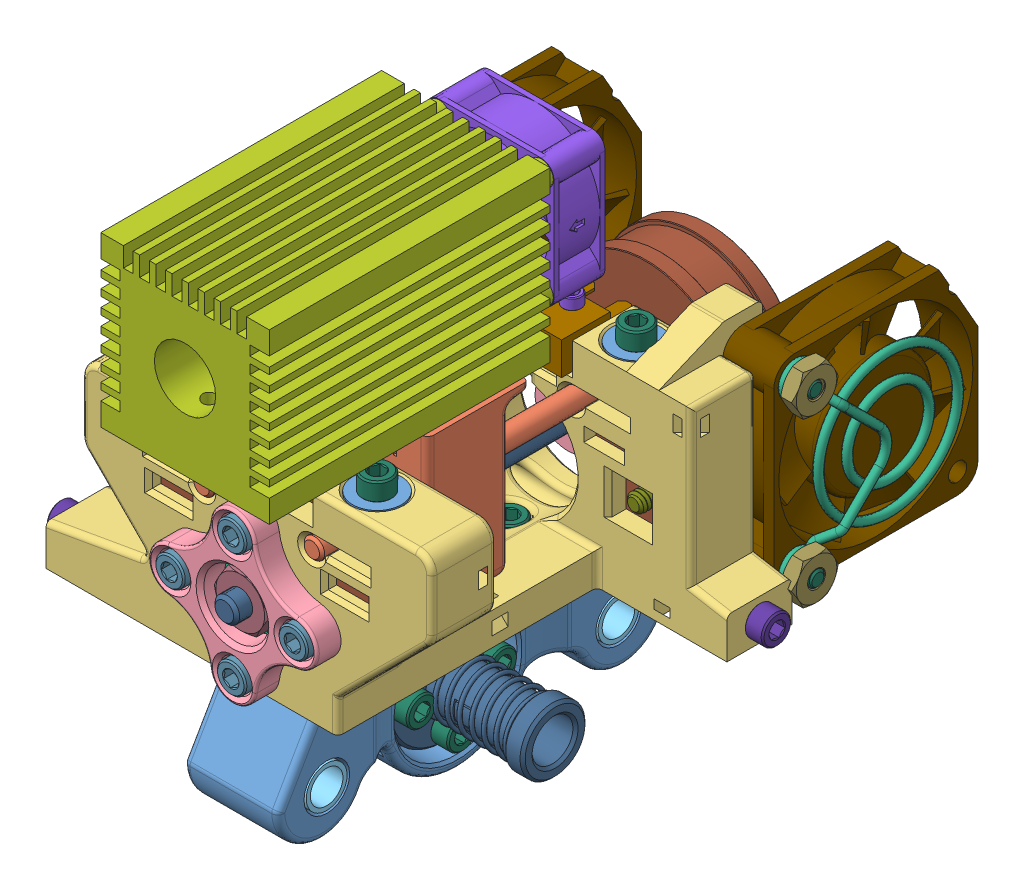
SolidWorks assembly LCSA-3, configuration LCSA-3. Lengths in mm.
Overall size (89.88 103.22 117.36).
86 component instances, 29 part files, 228 mates.
Components (placement in the parent):
- LCSAP-304-1: LCSAP-304 [LCSAP-304] at (-4.5942 14.1847 0) size (19.04 26.86 76.19)
- LCSAP-301-1: LCSAP-301 [LCSAP-301] at (12.8683 56.7614 1.1334) x (-1 0 0) z (0 1 0) size (35.07 23.37 31.49)
- LCSAP-302-1: LCSAP-302 [LCSAP-302] at (-20.4692 28.2182 33.02) x (0 0 -1) z (1 0 0) size (76.2 44.7 82.55)
- LCSAP-303-1: LCSAP-303 [LCSAP-303] at (-4.5942 44.7282 33.02) x (0 -1 0) z (0 0 1) size (33.02 33.02 4.76)
- 6659K650-1: 6659K650 [6659K65] at (6.2008 57.4282 1.1334) x (1 0 0) z (0 -1 0) size (10 6 10)
- 6659K650-2: 6659K650 [6659K65] at (-15.3892 57.4282 1.1334) x (-0.173648 -0.984808 0) z (-0.984808 0.173648 0) size (10 6 10)
- 19155K910-1: 19155K910 [19155K91] at (-42.5342 50.5682 -50.29) x (0 0 -1) z (0 1 0) size (34.05 4.8 39.2)
- 19155K910-2: 19155K910 [19155K91] at (33.3458 50.5682 -50.29) x (0 0 -1) z (0 -1 0) size (34.05 4.8 39.2)
- 94855A279-1: 94855A279 [94855A279] at (-9.3617 59.8094 -23.9712) size (4.76 1.94 4.76)
- 94855A279-2: 94855A279 [94855A279] at (0.1683 59.8094 -23.9712) x (0 0 -1) z (1 0 0) size (4.76 1.94 4.76)
- 94855A279-7: 94855A279 [94855A279] at (0.1683 59.8094 26.5113) x (0 0 -1) z (-1 0 0) size (4.76 1.94 4.76)
- 94855A279-8: 94855A279 [94855A279] at (-9.3567 59.8094 26.5113) x (0 0 -1) z (-1 0 0) size (4.76 1.94 4.76)
- 92185A081-1: 92185A081 [92185A081] at (0.1683 56.5257 -23.9712) x (0 0 1) z (0 -1 0) size (3.56 3.56 13.6)
- 92185A081-2: 92185A081 [92185A081] at (-9.3617 56.5257 -23.9712) x (0 0 1) z (0 -1 0) size (3.56 3.56 13.6)
- 92185A081-7: 92185A081 [92185A081] at (-9.3617 56.5257 26.5113) x (0 0 -1) z (0 -1 0) size (3.56 3.56 13.6)
- 92185A081-8: 92185A081 [92185A081] at (0.1683 56.5257 26.5113) x (0 0 -1) z (0 -1 0) size (3.56 3.56 13.6)
- 94855A283-6: 94855A283 [94855A283] at (-4.5942 44.7282 12.8809) x (0 -1 0) z (1 0 0) size (9.53 3.79 9.53)
- 90322A641-1: 90322A641 [90322A641] at (-4.5942 44.7282 4.445) x (0 0 -1) z (-0.968717 -0.248166 0) size (69.85 4.83 4.83)
- 94855A201-1: 94855A201 [94855A201] at (-4.5942 17.4311 16.51) x (0 0 -1) z (-1 0 0) size (7.94 3.39 7.94)
- 94855A201-2: 94855A201 [94855A201] at (-4.5942 17.4311 -16.51) x (0 0 1) z (1 0 0) size (7.94 3.39 7.94)
- 94855A201-3: 94855A201 [94855A201] at (7.4708 44.7282 30.48) x (-0.104528 -0.994522 0) z (-0.994522 0.104528 0) size (7.94 3.39 7.94)
- 94855A201-4: 94855A201 [94855A201] at (-21.8027 52.8641 26.67) x (0 0 1) z (1 0 0) size (7.94 3.39 7.94)
- 94855A201-5: 94855A201 [94855A201] at (12.6143 52.8641 26.67) x (0 0 -1) z (1 0 0) size (7.94 3.39 7.94)
- 94855A201-6: 94855A201 [94855A201] at (-4.5942 32.6632 30.48) x (0 1 0) z (-1 0 0) size (7.94 3.39 7.94)
- 94855A201-7: 94855A201 [94855A201] at (-16.6592 44.7282 30.48) x (0.994522 0.104528 0) z (-0.104528 0.994522 0) size (7.94 3.39 7.94)
- 94855A201-8: 94855A201 [94855A201] at (-21.8027 52.8641 -24.13) x (0 0 1) z (-1 0 0) size (7.94 3.39 7.94)
- 94855A283-5: 94855A283 [94855A283] at (-4.5942 44.7282 5.2609) x (0 -1 0) z (1 0 0) size (9.53 3.79 9.53)
- 94855A201-9: 94855A201 [94855A201] at (12.6143 52.8641 -24.13) x (0 0 -1) z (-1 0 0) size (7.94 3.39 7.94)
- 94855A201-11: 94855A201 [94855A201] at (-4.5942 56.7932 30.48) x (1 0 0) z (0 -1 0) size (7.94 3.39 7.94)
- 94855A201-13: 94855A201 [94855A201] at (16.2417 32.1869 -24.13) x (0 1 0) z (0 0 -1) size (7.94 3.39 7.94)
- 94855A201-15: 94855A201 [94855A201] at (-25.4301 32.1869 26.67) x (0 1 0) z (0 0 1) size (7.94 3.39 7.94)
- 94855A201-16: 94855A201 [94855A201] at (17.3558 44.7282 -22.7409) x (0 -1 0) z (1 0 0) size (7.94 3.39 7.94)
- 94855A201-18: 94855A201 [94855A201] at (-26.5442 44.7282 -22.7409) x (0 1 0) z (-1 0 0) size (7.94 3.39 7.94)
- 90480A007-1: 90480A007 [90480A007] at (-12.3333 15.6452 7.9375) x (0 -0.866025 -0.5) z (0 0.5 -0.866025) size (7.94 3.39 9.17)
- 90480A007-2: 90480A007 [90480A007] at (-12.3333 15.6452 -7.9375) x (0 -0.866025 0.5) z (0 -0.5 -0.866025) size (7.94 3.39 9.17)
- 90480A195-1: 90480A195 [90480A195] at (-4.5942 44.7282 34.6575) x (0 1 0) z (1 0 0) size (9.53 3.99 11)
- 90480A195-4: 90480A195 [90480A195] at (-4.5942 44.7282 26.4825) x (-0.866025 0.5 0) z (-0.5 -0.866025 0) size (9.53 3.99 11)
- 90480A007-3: 90480A007 [90480A007] at (-12.3333 7.7077 0) x (0 -0.5 0.866025) z (0 -0.866025 -0.5) size (7.94 3.39 9.17)
- 90480A007-5: 90480A007 [90480A007] at (-12.3333 23.5827 0) x (0 -0.5 0.866025) z (0 -0.866025 -0.5) size (7.94 3.39 9.17)
- 90480A007-7: 90480A007 [90480A007] at (-45.5233 34.5682 -34.29) x (0 0.5 -0.866025) z (0 0.866025 0.5) size (7.94 3.39 9.17)
- 90480A007-9: 90480A007 [90480A007] at (-45.5233 66.5682 -34.29) x (0 0.5 -0.866025) z (0 0.866025 0.5) size (7.94 3.39 9.17)
- 90480A007-11: 90480A007 [90480A007] at (36.3349 34.5682 -34.29) x (0 -0.5 -0.866025) z (0 -0.866025 0.5) size (7.94 3.39 9.17)
- 90480A007-13: 90480A007 [90480A007] at (36.3349 66.5682 -34.29) x (0 -0.5 -0.866025) z (0 -0.866025 0.5) size (7.94 3.39 9.17)
- 92196A145-5: 92196A145 [92196A145] at (-4.5942 56.7932 26.67) x (-0.805768 -0.592231 0) z (0 0 -1) size (5.74 5.74 11.87)
- 92196A145-6: 92196A145 [92196A145] at (7.4708 44.7282 26.67) x (-0.5 0.866025 0) z (0 0 -1) size (5.74 5.74 11.87)
- 92196A145-7: 92196A145 [92196A145] at (-16.6592 44.7282 26.67) x (-0.20766 0.978201 0) z (0 0 -1) size (5.74 5.74 11.87)
- 92196A145-8: 92196A145 [92196A145] at (-4.5942 32.6632 26.67) x (0.437601 -0.899169 0) z (0 0 -1) size (5.74 5.74 11.87)
- 92196A150-6: 92196A150 [92196A150] at (12.6143 51.5862 -24.13) x (0.866025 0 0.5) z (0 -1 0) size (5.74 5.74 19.85)
- 92196A150-7: 92196A150 [92196A150] at (12.6143 51.5862 26.67) x (0.866025 0 0.5) z (0 -1 0) size (5.74 5.74 19.85)
- 92196A150-9: 92196A150 [92196A150] at (-21.8027 51.5862 26.67) x (0.866025 0 0.5) z (0 -1 0) size (5.74 5.74 19.85)
- 92196A150-11: 92196A150 [92196A150] at (-21.8027 51.5862 -24.13) x (0.866025 0 0.5) z (0 -1 0) size (5.74 5.74 19.85)
- 92196A150-1: 92196A150 [92196A150] at (-16.6592 15.6452 7.9375) x (0 0.445229 0.895417) z (-1 0 0) size (5.74 5.74 19.85)
- 92196A150-2: 92196A150 [92196A150] at (-16.6592 15.6452 -7.9375) x (0 0.5 0.866025) z (-1 0 0) size (5.74 5.74 19.85)
- 92196A150-3: 92196A150 [92196A150] at (-4.5942 13.9307 16.51) x (0.884768 0 0.466031) z (0 -1 0) size (5.74 5.74 19.85)
- 92196A150-4: 92196A150 [92196A150] at (-4.5942 13.9307 -16.51) x (0.997638 0 -0.068685) z (0 -1 0) size (5.74 5.74 19.85)
- 92196A150-13: 92196A150 [92196A150] at (-16.6592 7.7077 0) x (0 -0.959127 0.282977) z (-1 0 0) size (5.74 5.74 19.85)
- 92196A150-15: 92196A150 [92196A150] at (-16.6592 23.5827 0) x (0 0.993694 -0.112128) z (-1 0 0) size (5.74 5.74 19.85)
- 92196A150-17: 92196A150 [92196A150] at (37.9933 34.5682 -34.29) x (0 0.866025 -0.5) z (1 0 0) size (5.74 5.74 19.85)
- 92196A150-19: 92196A150 [92196A150] at (37.6333 66.5682 -34.29) x (0 0.755509 0.655138) z (1 0 0) size (5.74 5.74 19.85)
- 92196A150-21: 92196A150 [92196A150] at (-47.1817 34.5682 -34.29) x (0 0.866025 0.5) z (-1 0 0) size (5.74 5.74 19.85)
- 92196A150-23: 92196A150 [92196A150] at (-46.8217 66.5682 -34.29) x (0 -0.795652 -0.605754) z (-1 0 0) size (5.74 5.74 19.85)
- 92196A153-1: 92196A153 [92196A153] at (-26.5442 44.7282 -18.78) size (5.74 5.74 29.4)
- 92196A153-2: 92196A153 [92196A153] at (17.3558 44.7282 -18.78) x (0.987351 0.158553 0) z (0 0 1) size (5.74 5.74 29.4)
- 92196A236-1: 92196A236 [92196A236] at (1.7558 32.1869 -24.13) x (0 0.971198 -0.238273) z (-1 0 0) size (5.74 5.74 38.92)
- 92196A236-2: 92196A236 [92196A236] at (-10.9442 32.1869 26.67) x (0 0.996692 0.081273) z (1 0 0) size (5.74 5.74 38.92)
- AD0412HB-G70-1: AD0412HB-G70 [AD0412HB-G70] at (23.3458 50.5682 -50.29) x (0 -1 0) z (1 0 0) size (40 40 10.64)
- AD0412HB-G70-2: AD0412HB-G70 [AD0412HB-G70] at (-42.5342 50.5682 -50.29) x (0 -1 0) z (1 0 0) size (40 40 10.64)
- 90126A509-1: 90126A509 [90126A509] at (12.6143 66.3182 -24.13) x (-0.715617 0 -0.698492) z (0.698492 0 -0.715617) size (9.53 1.14 9.53)
- 90126A509-2: 90126A509 [90126A509] at (12.6143 66.3182 26.67) x (-0.834429 0 -0.551115) z (0.551115 0 -0.834429) size (9.53 1.14 9.53)
- 90126A509-4: 90126A509 [90126A509] at (-21.8027 66.3182 26.67) x (-0.933615 0 -0.358277) z (0.358277 0 -0.933615) size (9.53 1.14 9.53)
- 90126A509-6: 90126A509 [90126A509] at (-21.8027 66.3182 -24.13) x (-0.991589 0 -0.129423) z (0.129423 0 -0.991589) size (9.53 1.14 9.53)
- 6112K34-2.5-1: 6112K34-2.5 [6112K34] at (6.2008 57.4282 -30.48) x (-1 0 0) z (0 0 1) size (4 4 63.5)
- 6112K34-2.5-2: 6112K34-2.5 [6112K34] at (-15.3892 57.4282 33.02) x (1 0 0) z (0 0 -1) size (4 4 63.5)
- 91292A113-1: 91292A113 [91292A113] at (3.6558 80.8289 -2.9306) x (-0.866025 0 0.5) z (0 1 0) size (5.5 5.5 13.21)
- 91292A113-2: 91292A113 [91292A113] at (-4.5942 80.8008 -2.9306) x (-0.866025 0 0.5) z (0 1 0) size (5.5 5.5 13.21)
- 91292A113-3: 91292A113 [91292A113] at (-12.8442 80.8289 -2.9306) x (-0.866025 0 0.5) z (0 1 0) size (5.5 5.5 13.21)
- WXZC000198-2-1: WXZC000198-2 [WXZC000198-2 ] at (-4.5942 44.7282 -27.845) x (-0.598924 0.800806 0) z (0 0 -1) size (12.67 12.7 12.7)
- 1688K300-1: 1688K300 [1688K3] at (-1.7005 14.1847 28.575) x (0 0 -1) z (-1 0 0) size (7.99 7.99 12.7)
- 1688K300-2: 1688K300 [1688K3] at (-1.7005 14.1847 -28.575) x (0 0.158553 -0.987351) z (-1 0 0) size (7.99 7.99 12.7)
- R1810-2Z-1: R1810-2Z [6153K15] at (-4.5942 44.7282 28.07) x (0.999864 -0.016468 0) z (0 0 1) size (16 16 5)
- 5.6MMTO18AC-1: 5.6MMTO18AC [5.6MMTO18AC] at (11.9058 104.5823 47.0694) x (-1 0 0) z (0 0 1) size (33 33 59.76)
- 2510S-1: 2510S [2510S] at (-4.5942 88.0823 -12.6931) x (0 1 0) z (0 0 -1) size (25 25 10)
- 19N602-1: 19N602 [19N602] at (5.2983 61.2382 -26.3212) x (-1 0 0) z (0 0 -1) size (19.9 6.4 16.76)
- 19N602-4: 19N602 [19N602] at (5.2983 67.6382 28.8613) x (-1 0 0) z (0 0 1) size (19.9 6.4 16.76)
- T8-AB-1: T8-AB [T8-AB] at (-4.5942 15.6452 0) x (0 -1 0) z (0 0 1) size (22.23 25.4 22.23)
- 14HR05-0504S-1: 14HR05-0504S [14HR05-0504S] at (-4.5942 44.7282 -43.18) size (50.25 36.5 24.5)
Mates (geometry in assembly coordinates):
- Coincident31: coincident anti-aligned: plane of LCSAP-304-1 through (-4.5942 18.8202 0) normal (0 -1 0); plane of 94855A201-1 through (-8.5629 18.8202 20.4788) normal (0 1 0)
- Concentric13: concentric anti-aligned: circle of LCSAP-304-1; circle of 94855A201-1
- Coincident32: coincident anti-aligned: plane of LCSAP-304-1 through (-8.5629 18.8202 20.4788) normal (1 0 0); plane of 94855A201-1 through (-8.5629 16.0421 20.4788) normal (-1 0 0)
- Coincident33: coincident anti-aligned: plane of LCSAP-304-1 through (-4.5942 18.8202 0) normal (0 -1 0); plane of 94855A201-2 through (-0.6254 18.8202 -20.4788) normal (0 1 0)
- Concentric14: concentric aligned: circle of LCSAP-304-1; circle of 94855A201-2
- Coincident34: coincident anti-aligned: plane of LCSAP-304-1 through (-0.6254 18.8202 -12.5412) normal (-1 0 0); plane of 94855A201-2 through (-0.6254 16.0421 -20.4788) normal (1 0 0)
- Coincident71: coincident aligned: plane of 92196A145-5 through (-4.5942 56.7932 38.1127) normal (0 0 1); plane of 92196A145-6 through (7.4708 44.7282 38.1127) normal (0 0 1)
- Coincident72: coincident aligned: plane of 92196A145-6 through (7.4708 44.7282 38.1127) normal (0 0 1); plane of 92196A145-8 through (-4.5942 32.6632 38.1127) normal (0 0 1)
- Coincident73: coincident aligned: plane of 92196A145-7 through (-16.6592 44.7282 38.1127) normal (0 0 1); plane of 92196A145-8 through (-4.5942 32.6632 38.1127) normal (0 0 1)
- Concentric51: concentric aligned: circle of LCSAP-301-1; circle of 94855A283-5
- Coincident78: coincident anti-aligned: plane of LCSAP-301-1 through (0.0413 48.0302 6.8484) normal (0 0 -1); plane of 94855A283-5 through (0.1683 49.4907 6.8484) normal (0 0 1)
- Parallel24: parallel aligned: plane of LCSAP-301-1 through (12.8683 40.0927 1.1334) normal (0 -1 0); plane of 94855A283-5 through (-9.3567 39.9657 3.6734) normal (0 -1 0)
- Concentric53: concentric aligned: circle of WXZC000198-2-1; cylinder of 90322A641-1 through (-4.5942 44.7282 39.37) axis (0 0 -1) radius 2.413
- Coincident84: coincident anti-aligned: cylinder of 90322A641-1 through (-4.5942 44.7282 39.37) axis (0 0 -1) radius 2.413; circle of 90480A195-1
- Coincident86: coincident anti-aligned: plane of R1810-2Z-1 through (-4.5288 48.6964 33.07) normal (0 0 1); plane of 90480A195-1 through (-7.3438 39.9657 33.07) normal (0 0 -1)
- Coincident89: coincident anti-aligned: plane of R1810-2Z-1 through (-4.5288 48.6964 28.07) normal (0 0 -1); plane of 90480A195-4 through (0.9051 44.7282 28.07) normal (0 0 1)
- Coincident90: coincident aligned: cylinder of 90322A641-1 through (-4.5942 44.7282 39.37) axis (0 0 -1) radius 2.413; circle of 90480A195-4
- Concentric54: concentric anti-aligned: circle of 5.6MMTO18AC-1; circle of 2510S-1
- Concentric55: concentric anti-aligned: cylinder of 5.6MMTO18AC-1 through (-14.5942 78.0823 -12.6931) axis (0 0 1) radius 2.3813; circle of 2510S-1
- Coincident91: coincident anti-aligned: plane of 5.6MMTO18AC-1 through (-14.5942 78.0823 -12.6931) normal (0 0 -1); plane of 2510S-1 through (-14.5942 98.0823 -12.6931) normal (0 0 1)
- Concentric56: concentric anti-aligned: plane of LCSAP-301-1; plane of 91292A113-1
- Parallel30: parallel aligned: plane of LCSAP-301-1 through (-22.0567 56.7614 -6.3596) normal (0 0 -1); plane of 91292A113-1 through (4.3775 69.7039 -1.6806) normal (0 0 -1)
- Concentric57: concentric anti-aligned: cylinder of LCSAP-301-1 through (-4.5942 82.8077 -2.9306) axis (0 -1 0) radius 2.8575; cylinder of 91292A113-2 through (-4.5942 67.8008 -2.9306) axis (0 1 0) radius 2.75
- Coincident94: coincident aligned: unknown of 91292A113-2; cone of LCSAP-301-1 through (-4.5942 70.6679 -2.9306) axis (0 1 0)
- Parallel31: parallel aligned: plane of LCSAP-301-1 through (-22.0567 56.7614 -6.3596) normal (0 0 -1); plane of 91292A113-2 through (-3.8725 69.6758 -1.6806) normal (0 0 -1)
- Concentric58: concentric anti-aligned: plane of LCSAP-301-1; plane of 91292A113-3
- Parallel32: parallel aligned: plane of LCSAP-301-1 through (-22.0567 56.7614 -6.3596) normal (0 0 -1); plane of 91292A113-3 through (-12.1225 69.7039 -1.6806) normal (0 0 -1)
- Coincident97: coincident anti-aligned: plane of LCSAP-301-1 through (-22.0567 71.5823 1.1334) normal (0 1 0); plane of 5.6MMTO18AC-1 through (11.9058 71.5823 -7.9306) normal (0 -1 0)
- Concentric64: concentric anti-aligned: circle of 91292A113-1; circle of 5.6MMTO18AC-1
- Concentric65: concentric anti-aligned: cylinder of 91292A113-3 through (-12.8442 67.8289 -2.9306) axis (0 1 0) radius 2.75; cylinder of 5.6MMTO18AC-1 through (-12.8442 84.2823 -2.9306) axis (0 -1 0) radius 1.5
- Coincident99: coincident anti-aligned: plane of 19N602-1 through (5.2983 67.6382 -26.3212) normal (0 1 0); plane of 92185A081-1 through (0.1683 67.6382 -23.9712) normal (0 -1 0)
- Concentric71: concentric aligned: plane of 19N602-1; plane of 92185A081-1
- Parallel36: parallel aligned: plane of 19N602-1 through (5.2983 67.6382 -16.7713) normal (0 0 1); plane of 92185A081-1 through (0.7411 68.3343 -24.9634) normal (0 0 1)
- Concentric72: concentric aligned: plane of 19N602-1; plane of 92185A081-2
- Parallel37: parallel aligned: plane of 19N602-1 through (5.2983 67.6382 -16.7713) normal (0 0 1); plane of 92185A081-2 through (-8.7889 68.3343 -24.9634) normal (0 0 1)
- Coincident107: coincident anti-aligned: plane of 92185A081-2 through (-9.3617 67.6382 -23.9712) normal (0 -1 0); plane of 19N602-1 through (5.2983 67.6382 -26.3212) normal (0 1 0)
- Coincident113: coincident anti-aligned: plane of 19N602-4 through (5.2983 67.6382 28.8613) normal (0 1 0); plane of 92185A081-8 through (0.1683 67.6382 26.5113) normal (0 -1 0)
- Concentric85: concentric aligned: unknown of 19N602-4; cylinder of 92185A081-8 through (0.1683 69.8226 26.5113) axis (0 -1 0) radius 1.778
- Parallel42: parallel aligned: plane of 19N602-4 through (5.2983 61.2382 19.3112) normal (0 0 -1); plane of 92185A081-8 through (-0.4045 68.3343 27.5034) normal (0 0 -1)
- Concentric86: concentric anti-aligned: plane of 19N602-4; plane of 92185A081-7
- Parallel43: parallel aligned: plane of 19N602-4 through (5.2983 61.2382 19.3112) normal (0 0 -1); plane of 92185A081-7 through (-9.9345 68.3343 27.5034) normal (0 0 -1)
- Coincident114: coincident anti-aligned: plane of 19N602-4 through (5.2983 67.6382 28.8613) normal (0 1 0); plane of 92185A081-7 through (-9.3617 67.6382 26.5113) normal (0 -1 0)
- Concentric90: concentric anti-aligned: cylinder of LCSAP-304-1 through (-4.5942 15.6452 0) axis (1 0 0) radius 12.065; cylinder of T8-AB-1 through (-4.5942 15.6452 0) axis (-1 0 0) radius 11.1125
- Concentric91: concentric anti-aligned: cylinder of LCSAP-304-1 through (-14.1124 7.7077 0) axis (1 0 0) radius 1.905; circle of T8-AB-1
- Coincident120: coincident anti-aligned: plane of LCSAP-304-1 through (-4.5942 15.6452 0) normal (1 0 0); plane of T8-AB-1 through (-4.5942 19.6452 0) normal (-1 0 0)
- Concentric92: concentric aligned: circle of LCSAP-304-1; cylinder of 92196A150-1 through (2.721 15.6452 7.9375) axis (-1 0 0) radius 2.8702
- Coincident121: coincident anti-aligned: plane of 92196A150-1 through (-0.7842 15.6452 7.9375) normal (-1 0 0); plane of T8-AB-1 through (-0.7842 26.7577 0) normal (1 0 0)
- Concentric93: concentric anti-aligned: cylinder of LCSAP-304-1 through (-14.1124 15.6452 -7.9375) axis (1 0 0) radius 1.905; cylinder of 92196A150-2 through (2.721 15.6452 -7.9375) axis (-1 0 0) radius 2.8702
- Coincident124: coincident anti-aligned: plane of 92196A150-2 through (-0.7842 15.6452 -7.9375) normal (-1 0 0); plane of T8-AB-1 through (-0.7842 26.7577 0) normal (1 0 0)
- Coincident126: coincident anti-aligned: plane of LCSAP-304-1 through (-10.9442 -1.8173 0) normal (-1 0 0); plane of 90480A007-2 through (-10.9442 20.2279 -7.9375) normal (1 0 0)
- Concentric94: concentric aligned: circle of 90480A007-2; circle of 92196A150-2
- Concentric95: concentric anti-aligned: circle of LCSAP-304-1; circle of 90480A007-1
- Coincident128: coincident anti-aligned: plane of LCSAP-304-1 through (-10.9442 -1.8173 0) normal (-1 0 0); plane of 90480A007-1 through (-10.9442 17.9366 11.9062) normal (1 0 0)
- Parallel47: parallel anti-aligned: plane of 90480A007-1 through (-13.7223 13.3538 11.9062) normal (0 0 1); plane of 90480A007-2 through (-13.7223 17.9366 -11.9062) normal (0 0 -1)
- Perpendicular1: perpendicular: plane of LCSAP-304-1 through (-4.5942 28.2182 0) normal (0 1 0); plane of 90480A007-2 through (-13.7223 13.3538 -3.9688) normal (0 0 1)
- Coincident136: coincident anti-aligned: plane of LCSAP-302-1 through (-4.5942 29.8057 16.51) normal (0 1 0); plane of 92196A150-3 through (-4.5942 29.8057 16.51) normal (0 -1 0)
- Concentric101: concentric aligned: cylinder of LCSAP-302-1 through (-4.5942 72.9182 -16.51) axis (0 -1 0) radius 3.175; cylinder of 92196A150-4 through (-4.5942 33.3109 -16.51) axis (0 -1 0) radius 2.8702
- Coincident137: coincident anti-aligned: plane of LCSAP-302-1 through (-4.5942 29.8057 -16.51) normal (0 1 0); plane of 92196A150-4 through (-4.5942 29.8057 -16.51) normal (0 -1 0)
- Concentric102: concentric anti-aligned: circle of LCSAP-302-1; cylinder of 14HR05-0504S-1 through (17.3558 44.7282 -46.18) axis (0 0 1) radius 1
- Concentric104: concentric anti-aligned: cylinder of LCSAP-302-1 through (-26.5442 44.7282 25.6839) axis (0 0 -1) radius 1.905; circle of 14HR05-0504S-1
- Coincident138: coincident anti-aligned: plane of LCSAP-302-1 through (-26.5442 44.7282 -43.18) normal (0 0 -1); plane of 14HR05-0504S-1 through (16.2163 34.9049 -43.18) normal (0 0 1)
- Coincident140: coincident anti-aligned: plane of LCSAP-302-1 through (-25.7714 54.2532 -17.78) normal (1 0 0); plane of 94855A201-8 through (-25.7714 54.2532 -28.0987) normal (-1 0 0)
- Coincident141: coincident anti-aligned: plane of LCSAP-302-1 through (-25.7714 51.4751 -17.78) normal (0 1 0); plane of 94855A201-8 through (-25.7714 51.4751 -28.0987) normal (0 -1 0)
- Coincident142: coincident anti-aligned: plane of LCSAP-302-1 through (11.2808 67.5882 33.02) normal (0 0 1); plane of LCSAP-303-1 through (8.3657 37.8008 33.02) normal (0 0 -1)
- Concentric105: concentric anti-aligned: cylinder of LCSAP-302-1 through (7.4708 44.7282 21.59) axis (0 0 1) radius 1.8415; cylinder of 92196A145-6 through (7.4708 44.7282 38.1127) axis (0 0 -1) radius 2.8702
- Concentric106: concentric aligned: circle of LCSAP-302-1; cylinder of 92196A145-5 through (-4.5942 56.7932 38.1127) axis (0 0 -1) radius 2.8702
- Coincident144: coincident anti-aligned: plane of LCSAP-302-1 through (8.6456 54.2532 20.32) normal (1 0 0); plane of 94855A201-5 through (8.6456 54.2532 30.6387) normal (-1 0 0)
- Coincident146: coincident anti-aligned: plane of LCSAP-302-1 through (8.6456 54.2532 20.32) normal (0 -1 0); plane of 94855A201-5 through (16.5831 54.2532 30.6387) normal (0 1 0)
- Concentric108: concentric anti-aligned: cylinder of LCSAP-302-1 through (-4.5942 32.6632 21.59) axis (0 0 1) radius 1.8415; cylinder of 92196A145-8 through (-4.5942 32.6632 38.1127) axis (0 0 -1) radius 2.8702
- Concentric109: concentric anti-aligned: circle of LCSAP-302-1; cylinder of 92196A145-7 through (-16.6592 44.7282 38.1127) axis (0 0 -1) radius 2.8702
- Concentric110: concentric anti-aligned: cylinder of LCSAP-303-1 through (-4.5942 32.6632 34.6075) axis (0 0 1) radius 3.175; cylinder of 92196A145-8 through (-4.5942 32.6632 38.1127) axis (0 0 -1) radius 2.8702
- Coincident147: coincident anti-aligned: plane of LCSAP-303-1 through (-4.5942 32.6632 34.6075) normal (0 0 1); circle of 92196A145-8
- Coincident148: coincident anti-aligned: plane of LCSAP-303-1 through (7.4708 44.7282 34.6075) normal (0 0 1); circle of 92196A145-6
- Concentric111: concentric anti-aligned: cylinder of LCSAP-303-1 through (7.4708 44.7282 34.6075) axis (0 0 1) radius 3.175; cylinder of 92196A145-6 through (7.4708 44.7282 38.1127) axis (0 0 -1) radius 2.8702
- Concentric112: concentric anti-aligned: cylinder of LCSAP-302-1 through (-4.5942 44.7282 33.02) axis (0 0 -1) radius 11.43; cylinder of WXZC000198-2-1 through (-4.5942 44.7282 -40.545) axis (0 0 1) radius 6.35
- Coincident149: coincident aligned: plane of LCSAP-302-1 through (11.2808 67.5882 33.02) normal (0 0 1); plane of R1810-2Z-1 through (-4.4755 51.9335 33.02) normal (0 0 1)
- Concentric114: concentric aligned: cylinder of LCSAP-303-1 through (-4.5942 44.7282 37.7825) axis (0 0 -1) radius 6.35; circle of R1810-2Z-1
- Concentric115: concentric anti-aligned: cylinder of LCSAP-302-1 through (6.2008 57.4282 -30.48) axis (0 0 1) radius 2.032; cylinder of 6112K34-2.5-1 through (6.2008 57.4282 33.02) axis (0 0 -1) radius 2
- Concentric116: concentric aligned: circle of LCSAP-302-1; circle of 6112K34-2.5-2
- Coincident244: coincident aligned: plane of LCSAP-302-1 through (11.2808 67.5882 33.02) normal (0 0 1); plane of 6112K34-2.5-1 through (6.2008 57.4282 33.02) normal (0 0 1)
- Coincident151: coincident aligned: plane of 6112K34-2.5-1 through (6.2008 57.4282 33.02) normal (0 0 1); plane of 6112K34-2.5-2 through (-15.3892 57.4282 33.02) normal (0 0 1)
- Coincident152: coincident anti-aligned: plane of LCSAP-302-1 through (3.109 41.196 29.0909) normal (0.104528 0.994522 0); plane of 94855A201-3 through (11.003 40.3663 31.8691) normal (-0.104528 -0.994522 0)
- Concentric117: concentric aligned: cylinder of LCSAP-301-1 through (-15.3892 57.4282 -6.3596) axis (0 0 1) radius 3.5; cylinder of 6112K34-2.5-2 through (-15.3892 57.4282 -30.48) axis (0 0 1) radius 2
- Concentric118: concentric anti-aligned: cylinder of LCSAP-301-1 through (6.2008 57.4282 3.9532) axis (0 0 1) radius 523.5988; cylinder of 6112K34-2.5-1 through (6.2008 57.4282 33.02) axis (0 0 -1) radius 2
- Coincident155: coincident anti-aligned: circle of LCSAP-301-1; plane of 91292A113-1 through (3.6558 70.8289 -2.9306) normal (0 1 0)
- Coincident156: coincident anti-aligned: circle of LCSAP-301-1; plane of 91292A113-3 through (-12.8442 70.8289 -2.9306) normal (0 1 0)
- Concentric120: concentric aligned: cylinder of WXZC000198-2-1 through (-4.5942 44.7282 -34.195) axis (0 0 -1) radius 2.5; cylinder of 14HR05-0504S-1 through (-4.5942 44.7282 -31.18) axis (0 0 -1) radius 2.25
- Distance8: distance = 0.635 mm anti-aligned: plane of WXZC000198-2-1 through (-4.5942 44.7282 -40.545) normal (0 0 -1); plane of 14HR05-0504S-1 through (-4.5942 44.7282 -41.18) normal (0 0 1)
- Distance9: distance = 12.7 mm anti-aligned: plane of 90322A641-1 through (-4.5942 44.7282 -30.48) normal (0 0 -1); plane of LCSAP-302-1 through (11.2808 67.5882 -17.78) normal (0 0 1)
- Coincident160: coincident anti-aligned: plane of LCSAP-302-1 through (6.4058 61.2382 33.02) normal (0 1 0); plane of 19N602-4 through (5.2983 61.2382 28.8613) normal (0 -1 0)
- Concentric121: concentric anti-aligned: circle of LCSAP-302-1; cylinder of 92185A081-8 through (0.1683 69.8226 26.5113) axis (0 -1 0) radius 1.778
- Parallel57: parallel aligned: plane of LCSAP-302-1 through (11.2808 67.5882 33.02) normal (0 0 1); plane of 19N602-4 through (5.2983 61.2382 28.8613) normal (0 0 1)
- Coincident162: coincident anti-aligned: plane of LCSAP-302-1 through (-17.8339 54.2532 20.32) normal (-1 0 0); plane of 94855A201-4 through (-17.8339 51.4751 22.7012) normal (1 0 0)
- Coincident164: coincident anti-aligned: plane of LCSAP-302-1 through (-25.7714 51.4751 20.32) normal (0 1 0); plane of 94855A201-4 through (-17.8339 51.4751 22.7012) normal (0 -1 0)
- Coincident166: coincident anti-aligned: plane of LCSAP-302-1 through (-20.4692 28.2182 28.8925) normal (0 0 -1); plane of 94855A279-7 through (2.5496 59.0157 28.8925) normal (0 0 1)
- Coincident167: coincident anti-aligned: plane of LCSAP-302-1 through (-20.4692 28.2182 28.8925) normal (0 0 -1); plane of 94855A279-8 through (-6.9754 59.0157 28.8925) normal (0 0 1)
- Coincident168: coincident anti-aligned: plane of LCSAP-302-1 through (2.5496 60.6032 28.8925) normal (0 -1 0); plane of 94855A279-8 through (-11.7379 60.6032 28.8925) normal (0 1 0)
- Coincident169: coincident anti-aligned: plane of LCSAP-302-1 through (-6.9754 60.6032 28.8925) normal (0 -1 0); plane of 94855A279-7 through (-2.2129 60.6032 28.8925) normal (0 1 0)
- Coincident170: coincident anti-aligned: plane of LCSAP-302-1 through (-6.9754 60.6032 28.8925) normal (-1 0 0); plane of 94855A279-8 through (-6.9754 59.0157 28.8925) normal (1 0 0)
- Coincident171: coincident anti-aligned: plane of LCSAP-302-1 through (-2.2129 60.6032 28.8925) normal (1 0 0); plane of 94855A279-7 through (-2.2129 59.0157 28.8925) normal (-1 0 0)
- Coincident172: coincident anti-aligned: plane of LCSAP-302-1 through (6.4058 61.2382 33.02) normal (0 1 0); plane of 19N602-1 through (5.2983 61.2382 -26.3212) normal (0 -1 0)
- Concentric126: concentric anti-aligned: circle of LCSAP-302-1; cylinder of 92185A081-1 through (0.1683 69.8226 -23.9712) axis (0 -1 0) radius 1.778
- Parallel58: parallel aligned: plane of LCSAP-302-1 through (11.2808 28.2182 -30.48) normal (0 0 -1); plane of 19N602-1 through (5.2983 67.6382 -26.3212) normal (0 0 -1)
- LimitDistance1: limit distance = 17.9047 mm anti-aligned: plane of LCSAP-301-1 through (12.8683 47.2364 1.1334) normal (0 0 -1); plane of 19N602-1 through (5.2983 67.6382 -16.7713) normal (0 0 1)
- Concentric127: concentric anti-aligned: circle of LCSAP-302-1; circle of 94855A201-5
- Coincident173: coincident anti-aligned: plane of LCSAP-302-1 through (-6.9754 59.0157 -26.3525) normal (0 1 0); plane of 94855A279-1 through (-11.7429 59.0157 -21.59) normal (0 -1 0)
- Coincident175: coincident anti-aligned: plane of LCSAP-302-1 through (2.5496 59.0157 -26.3525) normal (0 1 0); plane of 94855A279-2 through (2.5496 59.0157 -21.59) normal (0 -1 0)
- Coincident178: coincident anti-aligned: plane of LCSAP-302-1 through (2.5496 60.6032 -26.3525) normal (-1 0 0); plane of 94855A279-2 through (2.5496 60.6032 -21.59) normal (1 0 0)
- Concentric129: concentric anti-aligned: circle of 94855A279-2; cylinder of 92185A081-1 through (0.1683 69.8226 -23.9712) axis (0 -1 0) radius 1.778
- Concentric135: concentric anti-aligned: circle of 94855A279-1; cylinder of 92185A081-2 through (-9.3617 69.8226 -23.9712) axis (0 -1 0) radius 1.778
- Parallel60: parallel aligned: plane of LCSAP-302-1 through (-6.9754 60.6032 -26.3525) normal (-1 0 0); plane of 94855A279-1 through (-11.7429 60.6032 -26.3525) normal (-1 0 0)
- Concentric136: concentric anti-aligned: cylinder of LCSAP-304-1 through (-8.0187 14.1847 28.575) axis (-1 0 0) radius 3.9688; cylinder of 1688K300-1 through (-8.0505 14.1847 28.575) axis (1 0 0) radius 3.9942
- Coincident179: coincident aligned: circle of LCSAP-304-1; plane of 1688K300-1 through (-8.0505 14.1847 28.575) normal (-1 0 0)
- Concentric137: concentric anti-aligned: cylinder of LCSAP-304-1 through (-8.0187 14.1847 -28.575) axis (-1 0 0) radius 3.9688; cylinder of 1688K300-2 through (-8.0505 14.1847 -28.575) axis (1 0 0) radius 3.9942
- Coincident180: coincident aligned: circle of LCSAP-304-1; plane of 1688K300-2 through (-8.0505 14.1847 -28.575) normal (-1 0 0)
- Concentric138: concentric anti-aligned: cylinder of LCSAP-302-1 through (12.6143 66.3182 -24.13) axis (0 1 0) radius 4.7625; cylinder of 90126A509-1 through (12.6143 67.4612 -24.13) axis (0 -1 0) radius 4.7625
- Coincident181: coincident anti-aligned: plane of LCSAP-302-1 through (12.6143 66.3182 -24.13) normal (0 1 0); plane of 90126A509-1 through (12.6143 66.3182 -24.13) normal (0 -1 0)
- Concentric140: concentric anti-aligned: cylinder of 90126A509-1 through (12.6143 66.3182 -24.13) axis (0 1 0) radius 1.9812; cylinder of 92196A150-6 through (12.6143 70.9664 -24.13) axis (0 -1 0) radius 2.8702
- Coincident183: coincident anti-aligned: plane of 90126A509-1 through (12.6143 67.4612 -24.13) normal (0 1 0); plane of 92196A150-6 through (12.6143 67.4612 -24.13) normal (0 -1 0)
- Parallel61: parallel aligned: plane of LCSAP-302-1 through (11.2808 67.5882 -17.78) normal (0 0 1); plane of 92196A150-6 through (13.4163 68.8828 -25.5191) normal (0 0 1)
- Concentric141: concentric anti-aligned: cylinder of 90126A509-2 through (12.6143 66.3182 26.67) axis (0 1 0) radius 1.9812; cylinder of 92196A150-7 through (12.6143 70.9664 26.67) axis (0 -1 0) radius 2.8702
- Coincident185: coincident anti-aligned: plane of 90126A509-2 through (12.6143 67.4612 26.67) normal (0 1 0); plane of 92196A150-7 through (12.6143 67.4612 26.67) normal (0 -1 0)
- Concentric142: concentric anti-aligned: unknown of LCSAP-302-1; cylinder of 90126A509-2 through (12.6143 67.4612 26.67) axis (0 -1 0) radius 4.7625
- Coincident186: coincident anti-aligned: plane of LCSAP-302-1 through (12.6143 66.3182 26.67) normal (0 1 0); plane of 90126A509-2 through (12.6143 66.3182 26.67) normal (0 -1 0)
- Parallel62: parallel aligned: plane of LCSAP-302-1 through (11.2808 67.5882 33.02) normal (0 0 1); plane of 92196A150-7 through (13.4163 68.8828 25.2809) normal (0 0 1)
- Concentric144: concentric anti-aligned: cylinder of 90126A509-4 through (-21.8027 66.3182 26.67) axis (0 1 0) radius 1.9812; cylinder of 92196A150-9 through (-21.8027 70.9664 26.67) axis (0 -1 0) radius 2.8702
- Coincident188: coincident anti-aligned: plane of 90126A509-4 through (-21.8027 67.4612 26.67) normal (0 1 0); plane of 92196A150-9 through (-21.8027 67.4612 26.67) normal (0 -1 0)
- Concentric145: concentric anti-aligned: unknown of LCSAP-302-1; cylinder of 90126A509-4 through (-21.8027 67.4612 26.67) axis (0 -1 0) radius 4.7625
- Coincident189: coincident anti-aligned: plane of LCSAP-302-1 through (-21.8027 66.3182 26.67) normal (0 1 0); plane of 90126A509-4 through (-21.8027 66.3182 26.67) normal (0 -1 0)
- Parallel63: parallel aligned: plane of LCSAP-302-1 through (11.2808 67.5882 33.02) normal (0 0 1); plane of 92196A150-9 through (-21.0007 68.8828 25.2809) normal (0 0 1)
- Concentric147: concentric anti-aligned: cylinder of 90126A509-6 through (-21.8027 66.3182 -24.13) axis (0 1 0) radius 1.9812; cylinder of 92196A150-11 through (-21.8027 70.9664 -24.13) axis (0 -1 0) radius 2.8702
- Coincident191: coincident anti-aligned: plane of 90126A509-6 through (-21.8027 67.4612 -24.13) normal (0 1 0); plane of 92196A150-11 through (-21.8027 67.4612 -24.13) normal (0 -1 0)
- Concentric148: concentric anti-aligned: unknown of LCSAP-302-1; cylinder of 90126A509-6 through (-21.8027 67.4612 -24.13) axis (0 -1 0) radius 4.7625
- Coincident192: coincident anti-aligned: plane of LCSAP-302-1 through (-21.8027 66.3182 -24.13) normal (0 1 0); plane of 90126A509-6 through (-21.8027 66.3182 -24.13) normal (0 -1 0)
- Parallel64: parallel aligned: plane of LCSAP-302-1 through (11.2808 67.5882 -17.78) normal (0 0 1); plane of 92196A150-11 through (-21.0007 68.8828 -25.5191) normal (0 0 1)
- Concentric150: concentric anti-aligned: circle of 94855A201-8; cylinder of 92196A150-11 through (-21.8027 70.9664 -24.13) axis (0 -1 0) radius 2.8702
- Concentric151: concentric aligned: circle of 94855A201-4; cylinder of 92196A150-9 through (-21.8027 70.9664 26.67) axis (0 -1 0) radius 2.8702
- Coincident194: coincident anti-aligned: plane of LCSAP-302-1 through (8.6456 54.2532 -17.78) normal (1 0 0); plane of 94855A201-9 through (8.6456 51.4751 -20.1612) normal (-1 0 0)
- Coincident195: coincident anti-aligned: plane of LCSAP-302-1 through (8.6456 51.4751 -17.78) normal (0 1 0); plane of 94855A201-9 through (8.6456 51.4751 -20.1612) normal (0 -1 0)
- Concentric152: concentric aligned: cylinder of 92196A150-6 through (12.6143 70.9664 -24.13) axis (0 -1 0) radius 2.8702; unknown of 94855A201-9
- Coincident196: coincident anti-aligned: plane of LCSAP-302-1 through (-20.4692 28.2182 29.0909) normal (0 0 1); plane of 94855A201-3 through (3.9386 49.09 29.0909) normal (0 0 -1)
- Coincident197: coincident anti-aligned: plane of LCSAP-302-1 through (3.9386 49.09 29.0909) normal (0.994522 -0.104528 0); plane of 94855A201-3 through (3.9386 49.09 31.8691) normal (-0.994522 0.104528 0)
- Coincident198: coincident anti-aligned: plane of LCSAP-302-1 through (-0.6254 36.6319 29.0909) normal (-1 0 0); plane of 94855A201-6 through (-0.6254 28.6944 29.0909) normal (1 0 0)
- Coincident199: coincident anti-aligned: plane of LCSAP-302-1 through (-20.4692 28.2182 31.8691) normal (0 0 -1); plane of 94855A201-6 through (-8.5629 28.6944 31.8691) normal (0 0 1)
- Coincident200: coincident anti-aligned: plane of LCSAP-302-1 through (-8.5629 36.6319 29.0909) normal (0 -1 0); plane of 94855A201-6 through (-0.6254 36.6319 29.0909) normal (0 1 0)
- Coincident201: coincident anti-aligned: plane of LCSAP-302-1 through (-32.9116 47.0106 29.0909) normal (0.104528 -0.994522 0); plane of 94855A201-7 through (-21.021 48.2604 29.0909) normal (-0.104528 0.994522 0)
- Coincident202: coincident anti-aligned: plane of LCSAP-302-1 through (-20.4692 28.2182 31.8691) normal (0 0 -1); plane of 94855A201-7 through (-21.021 48.2604 31.8691) normal (0 0 1)
- Coincident203: coincident anti-aligned: plane of LCSAP-302-1 through (-13.127 49.09 29.0909) normal (-0.994522 -0.104528 0); plane of 94855A201-7 through (-12.2973 41.196 29.0909) normal (0.994522 0.104528 0)
- Concentric153: concentric aligned: cylinder of 90322A641-1 through (-4.5942 44.7282 39.37) axis (0 0 -1) radius 2.413; unknown of 94855A283-6
- Coincident204: coincident anti-aligned: plane of LCSAP-301-1 through (0.0413 48.0302 14.4684) normal (0 0 -1); plane of 94855A283-6 through (0.1683 49.4907 14.4684) normal (0 0 1)
- Parallel65: parallel aligned: plane of LCSAP-301-1 through (12.8683 40.0927 1.1334) normal (0 -1 0); plane of 94855A283-6 through (-9.3567 39.9657 11.2934) normal (0 -1 0)
- Coincident207: coincident anti-aligned: plane of LCSAP-302-1 through (-20.4692 28.2182 29.0909) normal (0 0 1); plane of 94855A201-11 through (-8.5629 52.8244 29.0909) normal (0 0 -1)
- Coincident208: coincident anti-aligned: plane of LCSAP-302-1 through (-8.5629 52.8244 29.0909) normal (0 1 0); plane of 94855A201-11 through (-8.5629 52.8244 31.8691) normal (0 -1 0)
- Coincident209: coincident anti-aligned: plane of LCSAP-302-1 through (-0.6254 52.8244 29.0909) normal (-1 0 0); plane of 94855A201-11 through (-0.6254 60.7619 31.8691) normal (1 0 0)
- Coincident211: coincident anti-aligned: plane of LCSAP-302-1 through (23.3458 60.2182 -38.1) normal (1 0 0); plane of AD0412HB-G70-1 through (23.3458 34.5682 -34.29) normal (-1 0 0)
- Coincident213: coincident anti-aligned: plane of LCSAP-302-1 through (14.8527 28.2182 33.02) normal (1 0 0); plane of 94855A201-13 through (14.8527 28.2182 -28.0987) normal (-1 0 0)
- Concentric161: concentric aligned: circle of LCSAP-302-1; circle of 94855A201-13
- Coincident214: coincident anti-aligned: plane of LCSAP-302-1 through (14.8527 36.1557 -28.0987) normal (0 0 1); plane of 94855A201-13 through (17.6308 28.2182 -28.0987) normal (0 0 -1)
- Coincident215: coincident anti-aligned: plane of LCSAP-304-1 through (-4.5942 28.2182 0) normal (0 1 0); plane of LCSAP-302-1 through (11.2808 28.2182 33.02) normal (0 -1 0)
- Concentric162: concentric anti-aligned: circle of 92196A150-3; circle of LCSAP-302-1
- Concentric163: concentric aligned: cylinder of LCSAP-302-1 through (-4.5942 72.9182 -16.51) axis (0 -1 0) radius 3.175; circle of 94855A201-2
- Concentric164: concentric anti-aligned: circle of LCSAP-302-1; circle of 94855A201-1
- Concentric165: concentric anti-aligned: unknown of T8-AB-1; cylinder of 92196A150-13 through (2.721 7.7077 0) axis (-1 0 0) radius 2.8702
- Coincident216: coincident anti-aligned: plane of T8-AB-1 through (-0.7842 26.7577 0) normal (1 0 0); plane of 92196A150-13 through (-0.7842 7.7077 0) normal (-1 0 0)
- Concentric166: concentric anti-aligned: unknown of T8-AB-1; cylinder of 92196A150-15 through (2.721 23.5827 0) axis (-1 0 0) radius 2.8702
- Coincident217: coincident anti-aligned: plane of T8-AB-1 through (-0.7842 26.7577 0) normal (1 0 0); plane of 92196A150-15 through (-0.7842 23.5827 0) normal (-1 0 0)
- Concentric167: concentric anti-aligned: cylinder of 92196A236-1 through (36.6808 32.1869 -24.13) axis (-1 0 0) radius 1.7526; unknown of LCSAP-302-1
- Concentric168: concentric aligned: cylinder of LCSAP-302-1 through (-70.6342 32.1869 26.67) axis (1 0 0) radius 1.905; cylinder of 92196A236-2 through (-45.8692 32.1869 26.67) axis (1 0 0) radius 1.7526
- Coincident219: coincident anti-aligned: plane of LCSAP-302-1 through (-24.0411 36.1557 22.7012) normal (0 0 1); plane of 94855A201-15 through (-26.8192 28.2182 22.7012) normal (0 0 -1)
- Coincident220: coincident anti-aligned: plane of LCSAP-302-1 through (-24.0411 28.2182 -30.48) normal (-1 0 0); plane of 94855A201-15 through (-24.0411 28.2182 30.6387) normal (1 0 0)
- Coincident221: coincident anti-aligned: plane of LCSAP-302-1 through (-24.0411 36.1557 22.7012) normal (0 -1 0); plane of 94855A201-15 through (-26.8192 36.1557 22.7012) normal (0 1 0)
- Concentric169: concentric aligned: circle of 92196A150-13; circle of 90480A007-3
- Coincident222: coincident anti-aligned: plane of LCSAP-304-1 through (-10.9442 -1.8173 0) normal (-1 0 0); plane of 90480A007-3 through (-10.9442 11.6764 -2.2914) normal (1 0 0)
- Parallel67: parallel anti-aligned: plane of 90480A007-3 through (-13.7223 11.6764 2.2914) normal (0 1 0); plane of LCSAP-302-1 through (11.2808 28.2182 33.02) normal (0 -1 0)
- Concentric170: concentric aligned: circle of 92196A150-15; circle of 90480A007-5
- Coincident223: coincident anti-aligned: plane of LCSAP-304-1 through (-10.9442 -1.8173 0) normal (-1 0 0); plane of 90480A007-5 through (-10.9442 27.5514 -2.2914) normal (1 0 0)
- Parallel68: parallel anti-aligned: plane of 90480A007-5 through (-13.7223 27.5514 2.2914) normal (0 1 0); plane of LCSAP-302-1 through (11.2808 28.2182 33.02) normal (0 -1 0)
- Parallel69: parallel anti-aligned: plane of LCSAP-302-1 through (11.2808 28.2182 33.02) normal (0 -1 0); plane of 90480A195-1 through (-1.8446 49.4907 36.245) normal (0 1 0)
- Parallel70: parallel aligned: plane of LCSAP-302-1 through (-20.4692 57.4282 -30.48) normal (0 1 0); plane of 90480A195-4 through (-7.3438 49.4907 24.895) normal (0 1 0)
- Concentric172: concentric anti-aligned: cylinder of LCSAP-302-1 through (21.7583 66.5682 -34.29) axis (-1 0 0) radius 3.175; cylinder of 92196A150-19 through (18.2531 66.5682 -34.29) axis (1 0 0) radius 2.8702
- Coincident227: coincident anti-aligned: plane of LCSAP-302-1 through (21.7583 66.5682 -34.29) normal (-1 0 0); plane of 92196A150-19 through (21.7583 66.5682 -34.29) normal (1 0 0)
- Concentric174: concentric anti-aligned: cylinder of LCSAP-302-1 through (-30.9467 66.5682 -34.29) axis (1 0 0) radius 3.175; cylinder of 92196A150-23 through (-27.4415 66.5682 -34.29) axis (-1 0 0) radius 2.8702
- Coincident229: coincident anti-aligned: plane of LCSAP-302-1 through (-30.9467 66.5682 -34.29) normal (1 0 0); plane of 92196A150-23 through (-30.9467 66.5682 -34.29) normal (-1 0 0)
- Concentric175: concentric aligned: unknown of 92196A150-21; unknown of 90480A007-7
- Parallel72: parallel anti-aligned: plane of AD0412HB-G70-2 through (24.0343 70.5682 -66.29) normal (0 1 0); plane of 90480A007-7 through (-46.9123 30.5994 -36.5814) normal (0 -1 0)
- Concentric176: concentric aligned: unknown of 92196A150-23; unknown of 90480A007-9
- Parallel73: parallel anti-aligned: plane of AD0412HB-G70-2 through (24.0343 70.5682 -66.29) normal (0 1 0); plane of 90480A007-9 through (-46.9123 62.5994 -36.5814) normal (0 -1 0)
- Concentric177: concentric aligned: unknown of 92196A150-17; unknown of 90480A007-11
- Parallel74: parallel anti-aligned: plane of AD0412HB-G70-1 through (89.9143 30.5682 -34.29) normal (0 -1 0); plane of 90480A007-11 through (37.7239 38.5369 -36.5814) normal (0 1 0)
- Concentric178: concentric aligned: unknown of 92196A150-19; unknown of 90480A007-13
- Parallel75: parallel anti-aligned: plane of AD0412HB-G70-1 through (89.9143 30.5682 -34.29) normal (0 -1 0); plane of 90480A007-13 through (37.7239 70.5369 -36.5814) normal (0 1 0)
- Concentric179: concentric anti-aligned: circle of LCSAP-302-1; cylinder of AD0412HB-G70-1 through (33.3458 66.5682 -34.29) axis (-1 0 0) radius 1.778
- Coincident236: coincident anti-aligned: plane of LCSAP-302-1 through (22.1183 34.5682 -34.29) normal (-1 0 0); plane of 92196A150-17 through (22.1183 34.5682 -34.29) normal (1 0 0)
- Concentric180: concentric aligned: cylinder of LCSAP-302-1 through (4.6558 34.5682 -34.29) axis (1 0 0) radius 3.175; cylinder of 92196A150-17 through (18.6131 34.5682 -34.29) axis (1 0 0) radius 2.8702
- Coincident237: coincident anti-aligned: plane of LCSAP-302-1 through (-31.3067 34.5682 -34.29) normal (1 0 0); plane of 92196A150-21 through (-31.3067 34.5682 -34.29) normal (-1 0 0)
- Concentric181: concentric aligned: cylinder of LCSAP-302-1 through (-13.8442 34.5682 -34.29) axis (-1 0 0) radius 3.175; cylinder of 92196A150-21 through (-27.8015 34.5682 -34.29) axis (-1 0 0) radius 2.8702
- Parallel77: parallel aligned: plane of LCSAP-302-1 through (-20.4692 28.2182 -38.1) normal (0 0 -1); plane of 92196A150-21 through (-29.8851 35.3702 -32.9009) normal (0 0 -1)
- Parallel78: parallel aligned: plane of LCSAP-302-1 through (-20.4692 28.2182 -38.1) normal (0 0 -1); plane of 92196A150-17 through (20.6967 33.7662 -32.9009) normal (0 0 -1)
- Concentric184: concentric anti-aligned: cylinder of AD0412HB-G70-1 through (33.3458 34.5682 -34.29) axis (-1 0 0) radius 1.778; cylinder of 92196A150-17 through (18.6131 34.5682 -34.29) axis (1 0 0) radius 2.8702
- Coincident240: coincident anti-aligned: plane of LCSAP-302-1 through (13.3871 48.6969 -24.13) normal (1 0 0); plane of 94855A201-16 through (13.3871 48.6969 -24.13) normal (-1 0 0)
- Coincident241: coincident anti-aligned: plane of LCSAP-302-1 through (-20.4692 28.2182 -24.13) normal (0 0 1); plane of 94855A201-16 through (21.3246 48.6969 -24.13) normal (0 0 -1)
- Concentric185: concentric aligned: circle of LCSAP-302-1; circle of 94855A201-16
- Coincident242: coincident anti-aligned: plane of LCSAP-302-1 through (-22.5754 48.6969 -24.13) normal (-1 0 0); plane of 94855A201-18 through (-22.5754 40.7594 -24.13) normal (1 0 0)
- Coincident243: coincident anti-aligned: plane of LCSAP-302-1 through (-20.4692 28.2182 -24.13) normal (0 0 1); plane of 94855A201-18 through (-30.5129 40.7594 -24.13) normal (0 0 -1)
- Concentric186: concentric aligned: circle of LCSAP-302-1; circle of 94855A201-18
- Concentric190: concentric aligned: cylinder of LCSAP-302-1 through (-26.5442 44.7282 -43.18) axis (0 0 1) radius 5.08; cylinder of 92196A153-1 through (-26.5442 44.7282 -44.18) axis (0 0 1) radius 1.7526
- Coincident250: coincident anti-aligned: plane of 14HR05-0504S-1 through (-4.5942 44.7282 -44.18) normal (0 0 -1); plane of 92196A153-1 through (-26.5442 44.7282 -44.18) normal (0 0 1)
- Concentric191: concentric aligned: cylinder of LCSAP-302-1 through (17.3558 44.7282 -43.18) axis (0 0 1) radius 5.08; cylinder of 92196A153-2 through (17.3558 44.7282 -44.18) axis (0 0 1) radius 1.7526
- Coincident251: coincident anti-aligned: plane of 14HR05-0504S-1 through (-4.5942 44.7282 -44.18) normal (0 0 -1); plane of 92196A153-2 through (17.3558 44.7282 -44.18) normal (0 0 1)
- Coincident252: coincident anti-aligned: plane of LCSAP-302-1 through (-45.8692 28.2182 -7.5649) normal (-1 0 0); plane of 92196A236-2 through (-45.8692 32.1869 26.67) normal (1 0 0)
- Coincident253: coincident anti-aligned: plane of LCSAP-302-1 through (36.6808 36.1557 -6.2534) normal (1 0 0); plane of 92196A236-1 through (36.6808 32.1869 -24.13) normal (-1 0 0)
- Coincident254: coincident anti-aligned: plane of LCSAP-302-1 through (-32.5342 28.2182 -38.1) normal (-1 0 0); plane of AD0412HB-G70-2 through (-32.5342 50.5682 -50.29) normal (1 0 0)
- Concentric192: concentric aligned: circle of LCSAP-302-1; circle of AD0412HB-G70-2
- Concentric193: concentric aligned: circle of LCSAP-302-1; circle of AD0412HB-G70-2
- Coincident256: coincident aligned: plane of AD0412HB-G70-2 through (-42.5342 34.5682 -34.29) normal (-1 0 0); plane of 19155K910-1 through (-42.5342 50.5682 -50.29) normal (-1 0 0)
- Concentric194: concentric anti-aligned: circle of AD0412HB-G70-2; circle of 19155K910-1
- Parallel79: parallel anti-aligned: plane of AD0412HB-G70-2 through (24.0343 30.5682 -34.29) normal (0 -1 0); plane of 19155K910-1 through (-42.5342 50.5682 -50.29) normal (0 1 0)
- Tangent3: tangent: plane of 90480A007-7 through (-44.1342 30.5994 -31.9986) normal (1 0 0); torus of 19155K910-1
- Tangent4: tangent: plane of 90480A007-9 through (-44.1342 62.5994 -31.9986) normal (1 0 0); edge_curve of 19155K910-1
- Coincident258: coincident aligned: plane of AD0412HB-G70-1 through (33.3458 50.5682 -50.29) normal (1 0 0); plane of 19155K910-2 through (33.3458 50.5682 -50.29) normal (1 0 0)
- Concentric195: concentric aligned: unknown of AD0412HB-G70-1; unknown of 19155K910-2
- Parallel81: parallel anti-aligned: plane of AD0412HB-G70-1 through (89.9143 70.5682 -66.29) normal (0 1 0); plane of 19155K910-2 through (33.3458 50.5682 -50.29) normal (0 -1 0)
- Tangent5: tangent: plane of 90480A007-11 through (34.9458 38.5369 -31.9986) normal (-1 0 0); edge_curve of 19155K910-2
- Tangent6: tangent: plane of 90480A007-13 through (34.9458 70.5369 -31.9986) normal (-1 0 0); edge_curve of 19155K910-2
- Concentric196: concentric anti-aligned: cylinder of LCSAP-301-1 through (6.2008 57.4282 -6.3596) axis (0 0 1) radius 3.5; cylinder of 6659K650-1 through (6.2008 57.4282 7.1334) axis (0 0 -1) radius 3.51
- Coincident259: coincident anti-aligned: plane of LCSAP-301-1 through (6.2008 57.4282 2.6334) normal (0 0 -1); plane of 6659K650-1 through (6.2008 57.4282 2.6334) normal (0 0 1)
- Concentric197: concentric aligned: unknown of LCSAP-301-1; cylinder of 6659K650-2 through (-15.3892 57.4282 7.1334) axis (0 0 -1) radius 3.51
- Coincident262: coincident anti-aligned: plane of LCSAP-301-1 through (-15.3892 57.4282 2.6334) normal (0 0 -1); plane of 6659K650-2 through (-15.3892 57.4282 2.6334) normal (0 0 1)
